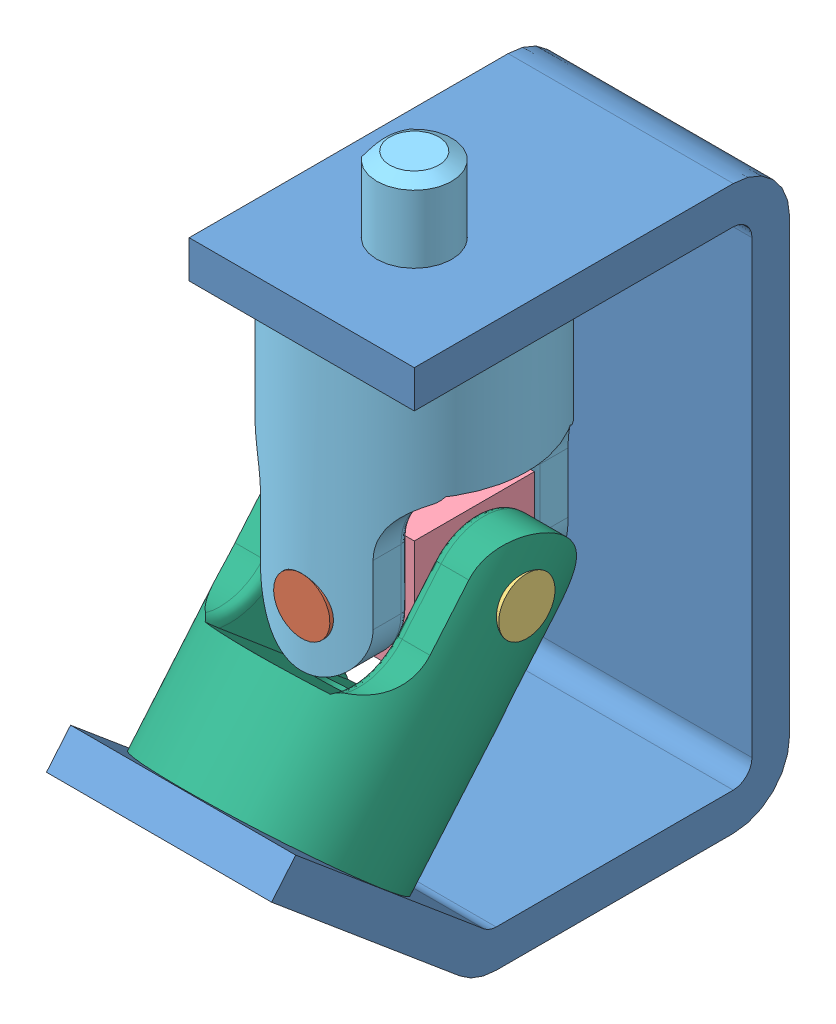
SolidWorks assembly Assem1, configuration Default. Lengths in mm.
Overall size (38.11 107.95 87.65).
7 component instances, 6 part files, 16 mates.
Components (placement in the parent):
- Bracket-1: Bracket [Default] at origin size (38.1 95.25 87.65)
- Long Pin-1: Long Pin [Default] at (0 44.45 57.15) x (0.97181 0.235764 0) z (0 0 -1) size (9.53 9.53 38.1)
- Pin-1: Pin [Default] at (-6.35 44.4492 38.1) x (0.000124 -0.936006 -0.351985) z (-1 -0.000133 0) size (9.53 9.53 12.7)
- Spider-1: Spider [Default] at (0 44.45 38.1) x (-1 -0.000133 0) z (0 0 -1) size (20.32 20.32 20.32)
- Yoke_Male-1: Yoke_Male [Default] at (0 34.925 38.1) x (-1 0 0) z (0 0 -1) size (38.1 66.67 38.1)
- Pin-2: Pin [Default] at (19.05 44.4525 38.1) x (-0.000127 0.958358 -0.285571) z (-1 -0.000133 0) size (9.53 9.53 12.7)
- Yoke_Female-2: Yoke_Female [Default] at (-0.001 51.7179 31.9434) x (-0.000086 0.646357 0.763035) z (1 0.000133 0) size (38.1 47.62 38.1)
Mates (geometry in assembly coordinates):
- Concentric1: concentric anti-aligned: cylinder of Bracket-1 through (0 -6.351 38.1) axis (0 1 0) radius 6.35; cylinder of Yoke_Male-1 through (0 101.6 38.1) axis (0 -1 0) radius 6.35
- Coincident1: coincident anti-aligned: plane of Bracket-1 through (19.05 82.55 3.175) normal (0 -1 0); plane of Yoke_Male-1 through (0 82.55 38.1) normal (0 1 0)
- Concentric2: concentric anti-aligned: cylinder of Spider-1 through (0 44.45 27.94) axis (0 0 1) radius 4.7625; cylinder of Yoke_Male-1 through (0 44.45 63.5) axis (0 0 -1) radius 4.7625
- Coincident2: coincident anti-aligned: plane of Spider-1 through (0 44.45 27.94) normal (0 0 -1); plane of Yoke_Male-1 through (19.05 31.3559 27.94) normal (0 0 1)
- Concentric3: concentric anti-aligned: cylinder of Spider-1 through (10.16 44.4513 38.1) axis (-1 -0.000133 0) radius 4.7625; cylinder of Yoke_Female-2 through (-25.4 44.4466 38.1) axis (1 0.000133 0) radius 4.7625
- Coincident3: coincident anti-aligned: plane of Spider-1 through (-10.1587 34.2887 27.94) normal (-1 -0.000133 0); plane of Yoke_Female-2 through (-10.1564 17.1214 36.2825) normal (1 0.000133 0)
- Concentric4: concentric aligned: cylinder of Long Pin-1 through (0 44.45 19.05) axis (0 0 1) radius 4.7625; cylinder of Spider-1 through (0 44.45 27.94) axis (0 0 1) radius 4.7625
- Concentric5: concentric anti-aligned: cylinder of Long Pin-1 through (0 44.45 19.05) axis (0 0 1) radius 4.7625; cylinder of Yoke_Male-1 through (0 44.45 63.5) axis (0 0 -1) radius 4.7625
- Tangent1: tangent aligned: plane of Long Pin-1 through (0 44.45 19.05) normal (0 0 -1); cylinder of Yoke_Male-1 through (0 82.55 38.1) axis (0 -1 0) radius 19.05
- Concentric6: concentric anti-aligned: cylinder of Pin-1 through (-19.05 44.4475 38.1) axis (1 0.000133 0) radius 4.7625; cylinder of Spider-1 through (10.16 44.4513 38.1) axis (-1 -0.000133 0) radius 4.7625
- Concentric7: concentric aligned: cylinder of Pin-1 through (-19.05 44.4475 38.1) axis (1 0.000133 0) radius 4.7625; cylinder of Yoke_Female-2 through (-25.4 44.4466 38.1) axis (1 0.000133 0) radius 4.7625
- Tangent3: tangent aligned: plane of Pin-1 through (-19.05 44.4475 38.1) normal (-1 -0.000133 0); cylinder of Yoke_Female-2 through (0.0039 15.3784 62.7262) axis (-0.000101 0.763035 -0.646357) radius 19.05
- Concentric8: concentric anti-aligned: cylinder of Spider-1 through (10.16 44.4513 38.1) axis (-1 -0.000133 0) radius 4.7625; cylinder of Pin-2 through (6.35 44.4508 38.1) axis (1 0.000133 0) radius 4.7625
- Concentric9: concentric aligned: cylinder of Pin-2 through (6.35 44.4508 38.1) axis (1 0.000133 0) radius 4.7625; cylinder of Yoke_Female-2 through (-25.4 44.4466 38.1) axis (1 0.000133 0) radius 4.7625
- Tangent4: tangent aligned: plane of Pin-2 through (19.05 44.4525 38.1) normal (1 0.000133 0); cylinder of Yoke_Female-2 through (0.0039 15.3784 62.7262) axis (-0.000101 0.763035 -0.646357) radius 19.05
- Angle1: planar angle = 0 rad aligned: plane of Yoke_Male-1 through (-4.8673 88.9 42.3589) normal (-1 0 0); plane of Bracket-1 through (-19.05 3.175 43.2944) normal (-1 0 0)
